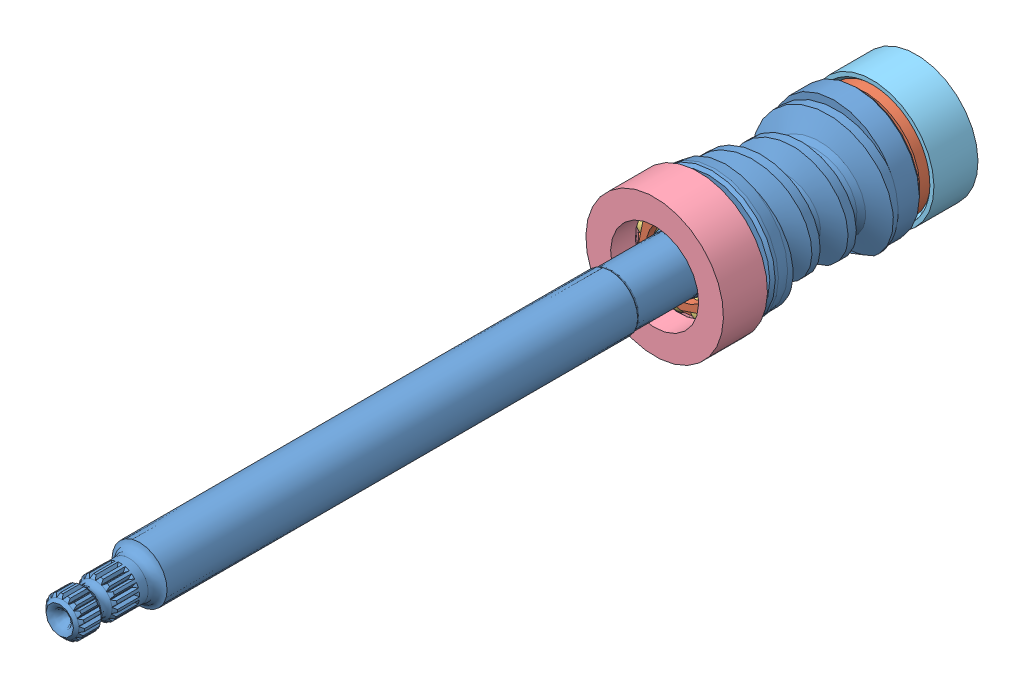
SolidWorks assembly подсборка червячного вала, configuration По умолчанию. Lengths in mm.
Overall size (68.76 68.76 311.16).
31 component instances, 5 part files, 8 mates.
Components (placement in the parent):
- вал с червяком-1: вал с червяком [Default] at origin size (50.58 50.33 303.38)
- подсборка подшипника-1: подсборка подшипника [По умолчанию] at (0 0 -94.0739) x (0 0 1) z (0.836092 -0.54859 0) size (10 40 40)
  - обойма подшипника 2-1: обойма подшипника 2 [По умолчанию] at origin size (10 40 40)
  - шарик подшипника-1: шарик подшипника [По умолчанию] at (-3.4256 15 0) size (8 8 8)
  - шарик подшипника-2: шарик подшипника [По умолчанию] at (-3.4256 12.9904 -7.5) x (1 0 0) z (0 0.5 0.866025) size (8 8 8)
  - шарик подшипника-3: шарик подшипника [По умолчанию] at (-3.4256 7.5 -12.9904) x (1 0 0) z (0 0.866025 0.5) size (8 8 8)
  - шарик подшипника-4: шарик подшипника [По умолчанию] at (-3.4256 0 -15) x (1 0 0) z (0 1 0) size (8 8 8)
  - шарик подшипника-5: шарик подшипника [По умолчанию] at (-3.4256 -7.5 -12.9904) x (1 0 0) z (0 0.866025 -0.5) size (8 8 8)
  - шарик подшипника-6: шарик подшипника [По умолчанию] at (-3.4256 -12.9904 -7.5) x (1 0 0) z (0 0.5 -0.866025) size (8 8 8)
  - шарик подшипника-7: шарик подшипника [По умолчанию] at (-3.4256 -15 0) x (1 0 0) z (0 0 -1) size (8 8 8)
  - шарик подшипника-8: шарик подшипника [По умолчанию] at (-3.4256 -12.9904 7.5) x (1 0 0) z (0 -0.5 -0.866025) size (8 8 8)
  - шарик подшипника-9: шарик подшипника [По умолчанию] at (-3.4256 -7.5 12.9904) x (1 0 0) z (0 -0.866025 -0.5) size (8 8 8)
  - шарик подшипника-10: шарик подшипника [По умолчанию] at (-3.4256 0 15) x (1 0 0) z (0 -1 0) size (8 8 8)
  - шарик подшипника-11: шарик подшипника [По умолчанию] at (-3.4256 7.5 12.9904) x (1 0 0) z (0 -0.866025 0.5) size (8 8 8)
  - шарик подшипника-12: шарик подшипника [По умолчанию] at (-3.4256 12.9904 7.5) x (1 0 0) z (0 -0.5 0.866025) size (8 8 8)
- подсборка подшипника-2: подсборка подшипника [По умолчанию] at (0 0 -33.2438) x (0 0 -1) z (-0.946737 -0.322007 0) size (10 40 40)
  - обойма подшипника 2-1: обойма подшипника 2 [По умолчанию] at origin size (10 40 40)
  - шарик подшипника-1: шарик подшипника [По умолчанию] at (-3.4256 15 0) size (8 8 8)
  - шарик подшипника-2: шарик подшипника [По умолчанию] at (-3.4256 12.9904 -7.5) x (1 0 0) z (0 0.5 0.866025) size (8 8 8)
  - шарик подшипника-3: шарик подшипника [По умолчанию] at (-3.4256 7.5 -12.9904) x (1 0 0) z (0 0.866025 0.5) size (8 8 8)
  - шарик подшипника-4: шарик подшипника [По умолчанию] at (-3.4256 0 -15) x (1 0 0) z (0 1 0) size (8 8 8)
  - шарик подшипника-5: шарик подшипника [По умолчанию] at (-3.4256 -7.5 -12.9904) x (1 0 0) z (0 0.866025 -0.5) size (8 8 8)
  - шарик подшипника-6: шарик подшипника [По умолчанию] at (-3.4256 -12.9904 -7.5) x (1 0 0) z (0 0.5 -0.866025) size (8 8 8)
  - шарик подшипника-7: шарик подшипника [По умолчанию] at (-3.4256 -15 0) x (1 0 0) z (0 0 -1) size (8 8 8)
  - шарик подшипника-8: шарик подшипника [По умолчанию] at (-3.4256 -12.9904 7.5) x (1 0 0) z (0 -0.5 -0.866025) size (8 8 8)
  - шарик подшипника-9: шарик подшипника [По умолчанию] at (-3.4256 -7.5 12.9904) x (1 0 0) z (0 -0.866025 -0.5) size (8 8 8)
  - шарик подшипника-10: шарик подшипника [По умолчанию] at (-3.4256 0 15) x (1 0 0) z (0 -1 0) size (8 8 8)
  - шарик подшипника-11: шарик подшипника [По умолчанию] at (-3.4256 7.5 12.9904) x (1 0 0) z (0 -0.866025 0.5) size (8 8 8)
  - шарик подшипника-12: шарик подшипника [По умолчанию] at (-3.4256 12.9904 7.5) x (1 0 0) z (0 -0.5 0.866025) size (8 8 8)
- вторая часть подшипника-2: вторая часть подшипника [По умолчанию] at (0 0 -21.6786) x (0 0 -1) z (0.522753 0.852484 0) size (16 50 50)
- вторая часть подшипника (меньшая)-1: вторая часть подшипника (меньшая) [По умолчанию] at (3.4387 3.2133 -107.9824) x (0 0 1) z (0.682748 -0.730654 0) size (16 45 45)
Mates (geometry in assembly coordinates):
- Концентричный1: concentric anti-aligned: cylinder of вал с червяком-1 through (0 0 -90.3785) axis (0 0 1) radius 23; cylinder of подсборка подшипника-1/обойма подшипника 2-1 through (0 0 -139.8249) axis (0 0 -1) radius 20
- Расстояние1: distance = 2.121 mm anti-aligned: plane of вал с червяком-1 through (0 0 -90.3785) normal (0 0 -1); plane of подсборка подшипника-1/обойма подшипника 2-1 through (-9.326 -14.2136 -92.4995) normal (0 0 1)
- Концентричный2: concentric anti-aligned: cylinder of вал с червяком-1 through (0 0 171) axis (0 0 -1) radius 10; cylinder of подсборка подшипника-2/обойма подшипника 2-1 through (0 0 12.5072) axis (0 0 1) radius 20
- Расстояние2: distance = 1.1817 mm anti-aligned: plane of подсборка подшипника-2/обойма подшипника 2-1 through (5.4741 -16.0945 -34.8183) normal (0 0 -1); plane of вал с червяком-1 through (0 0 -36) normal (0 0 1)
- Концентричный4: concentric anti-aligned: cylinder of вал с червяком-1 through (0 0 171) axis (0 0 -1) radius 10; cylinder of вторая часть подшипника-2 through (0 0 -2.7821) axis (0 0 1) radius 25
- Касательность6: tangent aligned: sphere of подсборка подшипника-2/шарик подшипника-12; cone of вторая часть подшипника-2 through (0 0 -25.1614) axis (0 0 1)
- Концентричный5: concentric anti-aligned: cylinder of вал с червяком-1 through (0 0 -90.3785) axis (0 0 1) radius 23; cylinder of вторая часть подшипника (меньшая)-1 through (0 0 -124.5357) axis (0 0 -1) radius 22.5
- Касательность7: tangent aligned: sphere of подсборка подшипника-1/шарик подшипника-11; cone of вторая часть подшипника (меньшая)-1 through (0 0 -102.1564) axis (0 0 -1)
